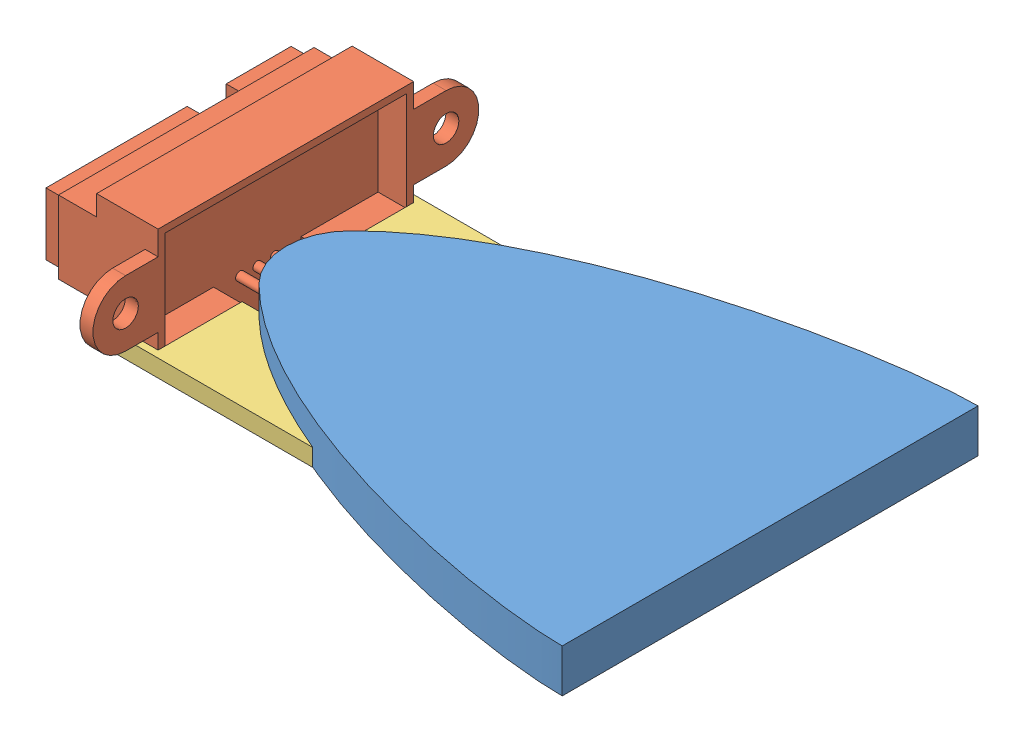
SolidWorks assembly train-distance-sensor-assembly, configuration Default. Lengths in mm.
Overall size (69.44 18.95 48).
3 component instances, 3 part files, 7 mates.
Components (placement in the parent):
- train-nose-profile-1: train-nose-profile [Default] at origin size (55.9 5 48)
- sharp-distance-sensor-1: sharp-distance-sensor [Default] at (-55.9 7.55 0) x (0 0 1) z (0 -1 0) size (44.55 15.24 18.95)
- distance-sensor-mount-1: distance-sensor-mount [Default] x (-1 0 0) z (0 -1 0) size (26.55 31.1 2)
Mates (geometry in assembly coordinates):
- Coincident1: coincident aligned: plane of train-nose-profile-1 through (0 0 0) normal (0 0 1); plane of sharp-distance-sensor-1
- Distance1: distance = 1 mm aligned: plane of train-nose-profile-1 through (0 0 0) normal (0 -1 0); plane of sharp-distance-sensor-1 through (-57.4 1 0) normal (0 -1 0)
- Tangent1: tangent anti-aligned: cylinder of train-nose-profile-1 through (-48.4 5 0) axis (0 -1 0) radius 7.5; plane of sharp-distance-sensor-1 through (-55.9 7.55 0) normal (1 0 0)
- InPlace1: in place: plane of train-nose-profile-1 through (0 0 0) normal (0 -1 0); plane of distance-sensor-mount-1 through (0 0 0) normal (0 -1 0); moOrthogonalPlaneRef_w of train-nose-profile-1 through (0 0 0) normal (0 -1 0); unknown of distance-sensor-mount-1; plane of train-nose-profile-1 through (0 0 0) normal (0 -1 0); line of distance-sensor-mount-1 through (55 -55 0) axis (0 0 -1); plane of train-nose-profile-1 through (0 0 0) normal (0 -1 0); unknown of distance-sensor-mount-1
- Coincident3: coincident aligned: plane of train-nose-profile-1; plane of distance-sensor-mount-1
- Coincident4: coincident aligned: moOrthogonalPlaneRef_w of train-nose-profile-1 through (0 0 0) normal (0 0 -1); plane of distance-sensor-mount-1
- Coincident5: coincident anti-aligned: moOrthogonalPlaneRef_w of train-nose-profile-1 through (0 0 0) normal (1 0 0); plane of distance-sensor-mount-1
